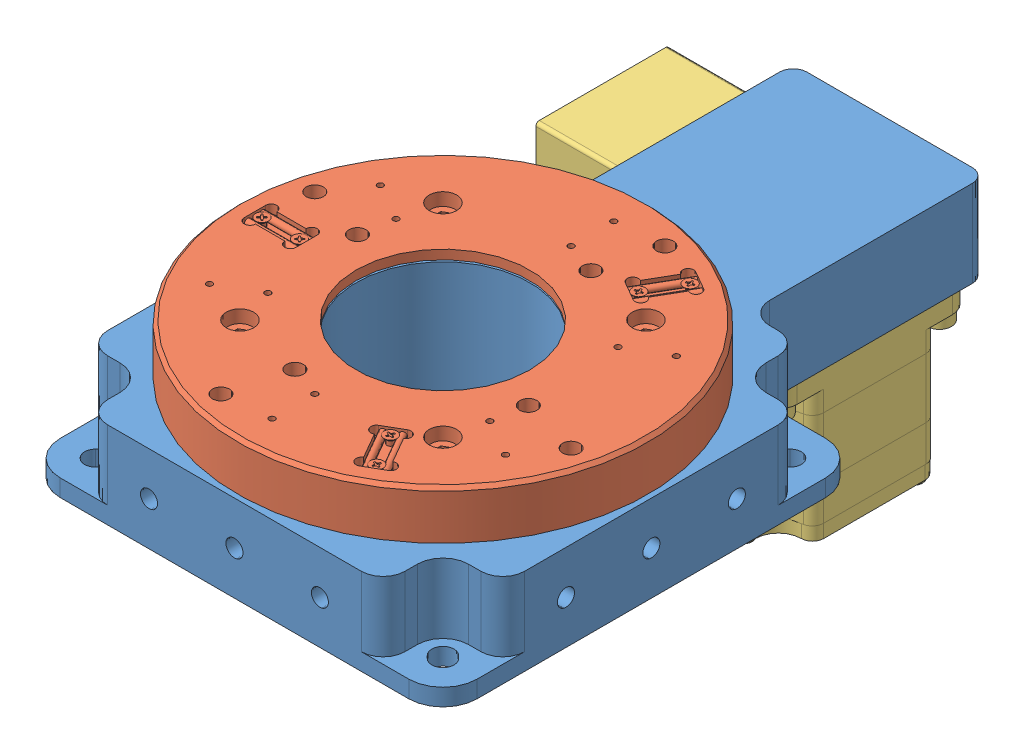
SolidWorks assembly RSB120, configuration RSB120xD-T3A. Lengths in mm.
Overall size (122 84.65 191.7).
3 component instances, 3 part files, 10 mates.
Components (placement in the parent):
- RSB120_base^RSB120-1: RSB120_base^RSB120 [RSB120] at origin (virtual)
- RSB120_top^RSB120-1: RSB120_top^RSB120 [Default] x (0 0 -1) z (1 0 0) (virtual)
- RSB120_motor^RSB120-1: RSB120_motor^RSB120 [RSB-T3A (short)] at (0 0 -98.15) x (0 0 1) z (0 1 0) (virtual)
Mates (geometry in assembly coordinates):
- Coincident1: coincident aligned: plane of RSB120_top^RSB120-1; plane of assembly through (0 0 0) normal (0 1 0)
- Coincident5: coincident: point of RSB120_top^RSB120-1; point of assembly
- Coincident6: coincident anti-aligned: plane of RSB120_base^RSB120-1 through (51 0 -51) normal (0 -1 0); plane of RSB120_motor^RSB120-1 through (0 0 -98.15) normal (0 1 0)
- Coincident7: coincident: point of RSB120_motor^RSB120-1; plane of assembly
- Distance1: distance = 98.15 mm aligned: plane of RSB120_motor^RSB120-1; plane of assembly through (0 0 0) normal (0 0 1)
- Coincident8: coincident anti-aligned: plane of RSB120_base^RSB120-1 through (51 25.38 -51) normal (0 1 0); plane of RSB120_motor^RSB120-1
- Coincident10: coincident anti-aligned: plane of RSB120_motor^RSB120-1; plane of RSB120_base^RSB120-1 through (51 25.38 -51) normal (0 1 0)
- Distance2: distance = 101.01 mm anti-aligned: plane of RSB120_motor^RSB120-1; plane of assembly through (0 0 0) normal (0 0 1)
- Coincident11: coincident anti-aligned: plane of RSB120_base^RSB120-1 through (51 0 -51) normal (0 -1 0); plane of RSB120_motor^RSB120-1 through (-22.7 0 -123.71) normal (0 1 0)
- Home Position: coincident anti-aligned: plane of RSB120_top^RSB120-1 through (0 0 0) normal (0 0 -1); plane of assembly through (0 0 0) normal (0 0 1)
